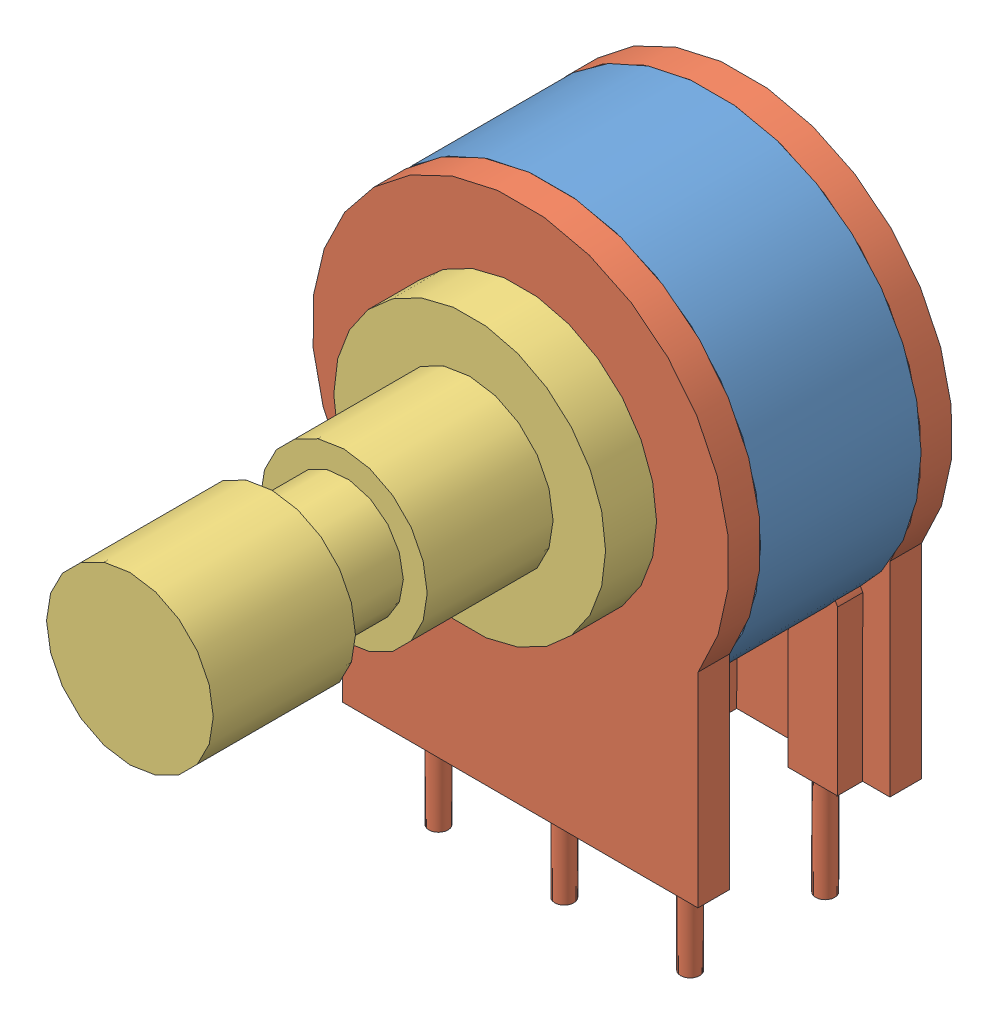
SolidWorks assembly Assem1, configuration Default. Lengths in mm.
Overall size (16.87 25.22 24.79).
4 component instances, 3 part files, 7 mates.
Components (placement in the parent):
- Body-1: Body [Default] at (-8.6298 0.3105 1.1044) size (16.84 16.84 6.48)
- Waffer-1: Waffer [Default] at (-8.6298 0.3105 -0.1656) x (0.999999 -0.001262 0) z (0 0 1) size (16.84 25.2 2.29)
- Waffer-2: Waffer [Default] at (-8.6298 0.3105 8.8514) x (-0.999999 0.001262 0) z (0 0 -1) size (16.84 25.2 2.29)
- Shaft-1: Shaft [Default] at (-8.6298 0.3105 8.8514) size (10.97 10.97 15.77)
Mates (geometry in assembly coordinates):
- Coincident1: coincident anti-aligned: plane of Body-1 through (-8.6298 0.3105 1.1044) normal (0 0 -1); plane of Waffer-1 through (-8.6298 0.3105 1.1044) normal (0 0 1)
- Coincident2: coincident aligned: circle of Body-1; circle of Waffer-1
- Coincident3: coincident anti-aligned: plane of Body-1 through (-8.6298 0.3105 7.5814) normal (0 0 1); plane of Waffer-2 through (-8.6298 0.3105 7.5814) normal (0 0 -1)
- Coincident4: coincident anti-aligned: circle of Body-1; circle of Waffer-2
- Parallel1: parallel anti-aligned: line of Waffer-1 through (-15.8074 -4.0918 1.1044) axis (-0.001262 -0.999999 0); line of Waffer-2 through (-15.8178 -12.3423 8.8514) axis (0.001262 0.999999 0)
- Coincident6: coincident anti-aligned: plane of Waffer-2 through (-8.6298 0.3105 8.8514) normal (0 0 1); plane of Shaft-1 through (-8.6298 0.3105 8.8514) normal (0 0 -1)
- Concentric1: concentric anti-aligned: circle of Waffer-2; circle of Shaft-1
